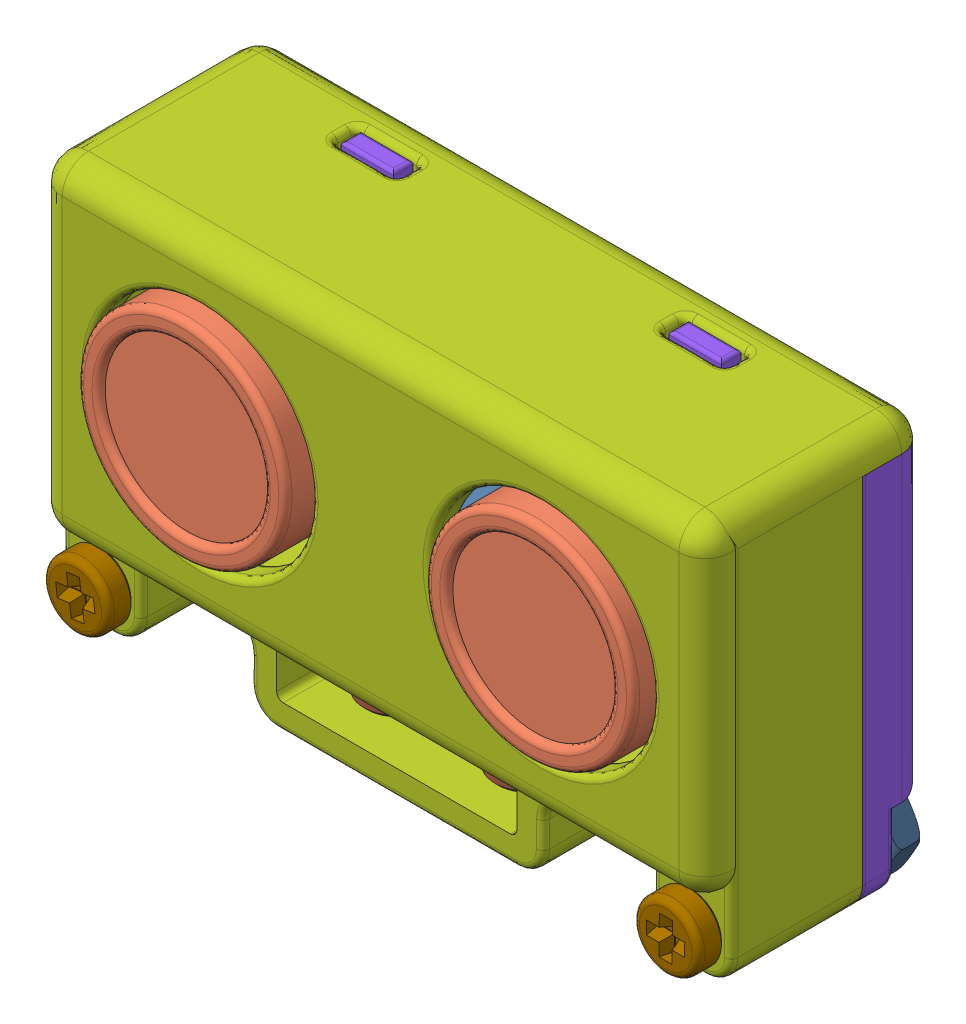
SolidWorks assembly porta-HC04, configuration Predeterminado. Lengths in mm.
Overall size (52.1 34 18.07).
23 component instances, 11 part files, 14 mates.
Components (placement in the parent):
- HC-SR04 Ping Sensor-1: HC-SR04 Ping Sensor [Default] at (-11.8933 3.1895 41.2842) x (0 -1 0) z (0 0 1) size (24.68 46 18.07)
  - PCB-1: PCB [Default] at origin size (20 46 1.75)
  - Transducer-1: Transducer [Default] at (0 -13.66 13.25) x (1 0 0) z (0 -1 0) size (15.88 12 15.88)
  - Transducer-2: Transducer [Default] at (0 12.84 13.25) x (1 0 0) z (0 -1 0) size (15.88 12 15.88)
  - 3 Pin Header 90 Degree-1: 3 Pin Header 90 Degree [Default] at (8.1775 0 -1.25) x (-1 0 0) z (0 -1 0) size (8 7.82 10)
  - 14 Pin SMT-1: 14 Pin SMT [Default] at (-0.1 -19 -0.85) x (0 -1 0) z (1 0 0) size (6 1.6 8.8)
  - 14 Pin SMT-2: 14 Pin SMT [Default] at (0 0.1174 -0.85) x (1 0 0) z (0 1 0) size (6 1.6 8.8)
  - 14 Pin SMT-3: 14 Pin SMT [Default] at (0 18.0274 -0.85) x (1 0 0) z (0 1 0) size (6 1.6 8.8)
  - Cap1 SMT-1: Cap1 SMT [Default] at (-1.505 7.9774 -0.9689) x (0 1 0) z (-1 0 0) size (4.5 1.84 1.75)
  - Cap1 SMT-2: Cap1 SMT [Default] at (6.585 7.9774 -0.9689) x (0 1 0) z (-1 0 0) size (4.5 1.84 1.75)
  - Cap1 SMT-3: Cap1 SMT [Default] at (-6.585 7.9774 -0.9689) x (0 1 0) z (-1 0 0) size (4.5 1.84 1.75)
  - Cap1 SMT-4: Cap1 SMT [Default] at (4.045 7.9774 -0.9689) x (0 1 0) z (-1 0 0) size (4.5 1.84 1.75)
  - Cap1 SMT-5: Cap1 SMT [Default] at (1.505 7.9774 -0.9689) x (0 1 0) z (-1 0 0) size (4.5 1.84 1.75)
  - Cap1 SMT-6: Cap1 SMT [Default] at (-4.045 7.9774 -0.9689) x (0 1 0) z (-1 0 0) size (4.5 1.84 1.75)
  - HC-SR04 Crystal-1: HC-SR04 Crystal [Default] at (-8.05 0 1.75) x (0 -1 0) z (0 0 1) size (10 3.5 2.7)
- porta-HC04-1-1: porta-HC04-1 [Predeterminado] at (-12.1932 3.1831 53.9658) size (51 31 17)
- porta-HC04-2-1: porta-HC04-2 [Predeterminado] at (-12.1932 0.9965 41.9658) size (51 31 5)
- M3-Tornillo-15mm-1: M3-Tornillo-15mm [Predeterminado] at (10.3068 -12.3169 51.9658) x (0.999941 -0.010837 0) z (-0.010837 -0.999941 0) size (5 17 5)
- M3-Tornillo-15mm-2: M3-Tornillo-15mm [Predeterminado] at (-34.6932 -12.3169 51.9658) x (0.992097 0.125471 0) z (0.125471 -0.992097 0) size (5 17 5)
- M3-Tuerca-1: M3-Tuerca [Default] at (10.3068 -12.3169 38.4658) x (1 0 0) z (0 -1 0) size (7.1 2.77 6.25)
- M3-Tuerca-2: M3-Tuerca [Default] at (-34.6932 -12.3169 38.4658) x (1 0 0) z (0 -1 0) size (7.1 2.77 6.25)
- M3-Tornillo-5mm-1: M3-Tornillo-5mm [Predeterminado] at (-7.1932 -13.3169 46.9658) size (5 7 5)
- M3-Tornillo-5mm-2: M3-Tornillo-5mm [Predeterminado] at (-17.1932 -13.3169 46.9658) size (5 7 5)
Mates (geometry in assembly coordinates):
- Coincidente1: coincident aligned: circle of porta-HC04-1-1; circle of porta-HC04-2-1
- Coincidente3: coincident aligned: plane of HC-SR04 Ping Sensor-1/3 Pin Header 90 Degree-1 through (-15.1133 -11.4905 36.9658) normal (0 0 -1); plane of porta-HC04-2-1 through (-35.6932 13.6831 36.9658) normal (0 0 -1)
- Concéntrica1: concentric anti-aligned: circle of porta-HC04-1-1; cylinder of M3-Tornillo-5mm-1 through (-7.1932 -18.3169 46.9658) axis (0 1 0) radius 1.5
- Concéntrica2: concentric anti-aligned: circle of porta-HC04-1-1; cylinder of M3-Tornillo-5mm-2 through (-17.1932 -18.3169 46.9658) axis (0 1 0) radius 1.5
- Concéntrica3: concentric aligned: cylinder of porta-HC04-1-1 through (10.3068 -12.3169 41.9658) axis (0 0 1) radius 1.75; cylinder of M3-Tornillo-15mm-1 through (10.3068 -12.3169 36.9658) axis (0 0 1) radius 1.5
- Concéntrica4: concentric aligned: cylinder of porta-HC04-1-1 through (-34.6932 -12.3169 41.9658) axis (0 0 1) radius 1.75; cylinder of M3-Tornillo-15mm-2 through (-34.6932 -12.3169 36.9658) axis (0 0 1) radius 1.5
- Coincidente4: coincident anti-aligned: plane of porta-HC04-1-1 through (-12.1932 3.1831 51.9658) normal (0 0 1); plane of M3-Tornillo-15mm-2 through (-34.6932 -12.3169 51.9658) normal (0 0 -1)
- Coincidente5: coincident anti-aligned: plane of porta-HC04-1-1 through (-3.0373 -13.3169 41.9658) normal (0 1 0); plane of M3-Tornillo-5mm-1 through (-7.1932 -13.3169 46.9658) normal (0 -1 0)
- Coincidente6: coincident anti-aligned: plane of porta-HC04-1-1 through (-3.0373 -13.3169 41.9658) normal (0 1 0); plane of M3-Tornillo-5mm-2 through (-17.1932 -13.3169 46.9658) normal (0 -1 0)
- Coincidente7: coincident anti-aligned: plane of porta-HC04-1-1 through (-12.1932 3.1831 51.9658) normal (0 0 1); plane of M3-Tornillo-15mm-1 through (10.3068 -12.3169 51.9658) normal (0 0 -1)
- Concéntrica5: concentric anti-aligned: cylinder of M3-Tornillo-15mm-1 through (10.3068 -12.3169 36.9658) axis (0 0 1) radius 1.5; cylinder of M3-Tuerca-1 through (10.3068 -12.3169 39.4658) axis (0 0 -1) radius 1.25
- Concéntrica6: concentric anti-aligned: cylinder of M3-Tornillo-15mm-2 through (-34.6932 -12.3169 36.9658) axis (0 0 1) radius 1.5; cylinder of M3-Tuerca-2 through (-34.6932 -12.3169 39.4658) axis (0 0 -1) radius 1.25
- Coincidente8: coincident anti-aligned: plane of porta-HC04-2-1 through (-12.1932 0.9965 39.4658) normal (0 0 -1); plane of M3-Tuerca-1 through (10.3068 -12.3169 39.4658) normal (0 0 1)
- Coincidente9: coincident anti-aligned: plane of porta-HC04-2-1 through (-12.1932 0.9965 39.4658) normal (0 0 -1); plane of M3-Tuerca-2 through (-34.6932 -12.3169 39.4658) normal (0 0 1)
